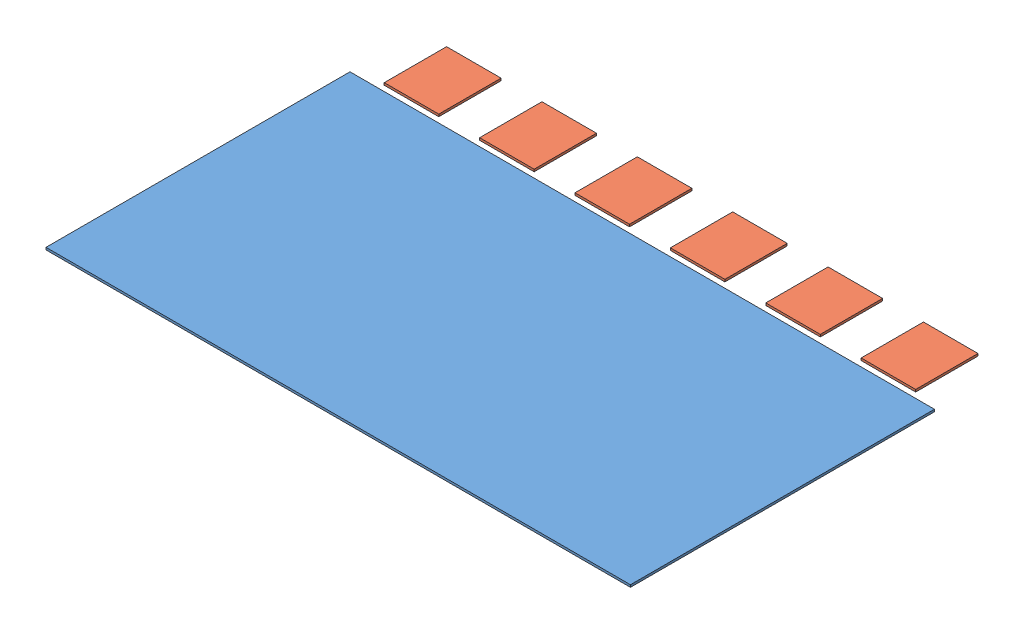
SolidWorks assembly IST Silicon Sensor and APV assy rev 5_11, configuration Default. Lengths in mm.
Overall size (76.9 0.3 49.22).
7 component instances, 2 part files, 4 mates.
Components (placement in the parent):
- IST Silicon Sensor rev1-2: IST Silicon Sensor rev1 [Default] x (-1 0 0) z (0 0 -1) size (76.9 0.3 40)
- IST APV 25 Chip rev1-37: IST APV 25 Chip rev1 [Default] at (31.375 0 -25.119) x (0 0 1) z (-1 0 0) size (8.2 0.3 7.17)
- IST APV 25 Chip rev1-2: IST APV 25 Chip rev1 [Default] at (18.825 0 -25.119) x (0 0 1) z (-1 0 0) size (8.2 0.3 7.17)
- IST APV 25 Chip rev1-3: IST APV 25 Chip rev1 [Default] at (6.275 0 -25.119) x (0 0 1) z (-1 0 0) size (8.2 0.3 7.17)
- IST APV 25 Chip rev1-4: IST APV 25 Chip rev1 [Default] at (-6.275 0 -25.119) x (0 0 1) z (-1 0 0) size (8.2 0.3 7.17)
- IST APV 25 Chip rev1-5: IST APV 25 Chip rev1 [Default] at (-18.825 0 -25.119) x (0 0 1) z (-1 0 0) size (8.2 0.3 7.17)
- IST APV 25 Chip rev1-6: IST APV 25 Chip rev1 [Default] at (-31.375 0 -25.119) x (0 0 1) z (-1 0 0) size (8.2 0.3 7.17)
Mates (geometry in assembly coordinates):
- Coincident1: coincident aligned: plane of IST Silicon Sensor rev1-2 through (-38.45 0 -20) normal (0 -1 0); plane of IST APV 25 Chip rev1-37 through (27.7875 0 -21.019) normal (0 -1 0)
- Distance2: distance = 5.119 mm: plane of IST Silicon Sensor rev1-2 through (38.45 0.3 -20) normal (0 0 -1); point of IST APV 25 Chip rev1-37
- Parallel1: parallel anti-aligned: plane of IST Silicon Sensor rev1-2 through (38.45 0.3 -20) normal (0 0 -1); plane of IST APV 25 Chip rev1-37 through (34.9625 0.3 -21.019) normal (0 0 1)
- Distance4: distance = 7.075 mm: point of IST APV 25 Chip rev1-37; plane of IST Silicon Sensor rev1-2 through (38.45 0.3 20) normal (1 0 0)
